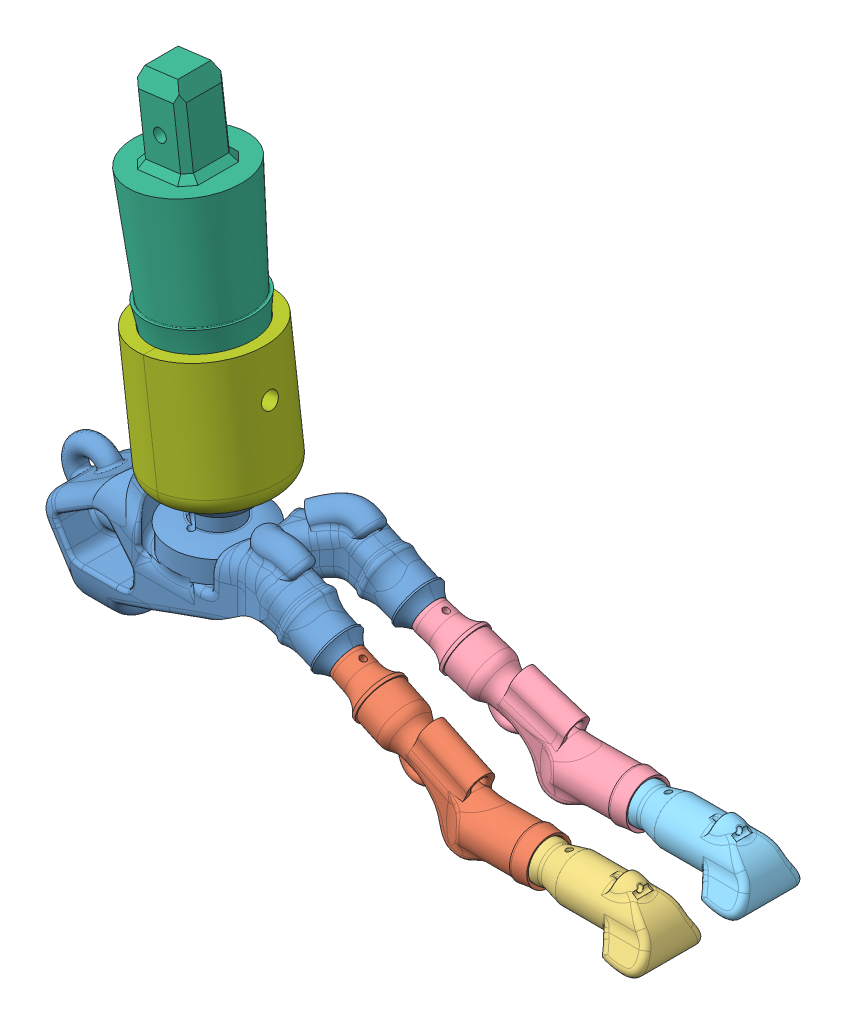
SolidWorks assembly Foot, configuration Default. Lengths in mm.
Overall size (260.5 205.9 79.33).
8 component instances, 7 part files, 11 mates.
Components (placement in the parent):
- Talus - New-1: Talus - New [Default] at origin size (131.32 86.19 51)
- Metatarsals-1: Metatarsals [Default] at (104.0952 -44.3034 18.1531) x (-0.929116 0.366544 -0.048875) z (0.042994 -0.024198 -0.998782) size (95.04 30.95 38.02)
- Phalanges-1: Phalanges [Default] at (172.2396 -55.1541 19.5999) size (57.16 24.44 28.69)
- Metatarsals - Left side-1: Metatarsals - Left side [Default] at (104.1326 -44.2161 -17.9587) x (-0.930097 0.364252 0.047332) z (-0.050841 -0.000045 -0.998707) size (95.04 30.95 38.02)
- Phalanges - Left side-1: Phalanges - Left side [Default] at (172.3053 -54.9301 -19.5095) size (57.16 24.44 28.69)
- Tibial End-1: Tibial End [Default] at (0.8729 -6.9424 0) x (0 0 1) z (-0.992187 -0.124756 0) size (42.45 113.08 48.21)
- Sleeve-4: Sleeve [Default] at (0.9802 -7.7957 0) x (-0.992187 -0.124756 0) z (0 0 -1) size (26.42 52.07 48.26)
- Sleeve-5: Sleeve [Default] at (0.9802 -7.7957 0) x (0.992187 0.124756 0) z (0 0 1) size (26.42 52.07 48.26)
Mates (geometry in assembly coordinates):
- Concentric1: concentric: sphere of Metatarsals-1; sphere of Talus - New-1
- Concentric2: concentric: sphere of Phalanges-1; sphere of Metatarsals-1
- Concentric3: concentric: sphere of Talus - New-1; sphere of Metatarsals - Left side-1
- Concentric4: concentric: sphere of Phalanges - Left side-1; sphere of Metatarsals - Left side-1
- Coincident12: coincident: sphere of Talus - New-1; circle of Tibial End-1
- Parallel4: parallel: plane of Talus - New-1 through (0 0 17.78) normal (0 0 1); plane of Tibial End-1 through (-25.2138 124.1775 9.525) normal (0 0 1)
- LimitAngle3: limit planar angle = 1.695878 rad: plane of Tibial End-1 through (-6.3127 126.5541 9.525) normal (0.992187 0.124756 0); plane of assembly through (0 0 0) normal (0 1 0)
- Concentric5: concentric: cylinder of Tibial End-1 through (17.8825 27.7092 0) axis (-0.992187 -0.124756 0) radius 3.302; cylinder of Sleeve-5 through (35.1548 29.881 0) axis (-0.992187 -0.124756 0) radius 3.302
- Coincident13: coincident: plane of Sleeve-4 through (-5.3574 42.6074 0) normal (-0.124756 0.992187 0); plane of Sleeve-5 through (-5.3574 42.6074 0) normal (-0.124756 0.992187 0)
- Concentric6: concentric: circle of Tibial End-1; circle of Sleeve-5
- Coincident15: coincident: plane of Sleeve-4 through (0.9802 -7.7957 0) normal (0.992187 0.124756 0); plane of Sleeve-5 through (0.9802 -7.7957 0) normal (-0.992187 -0.124756 0)
